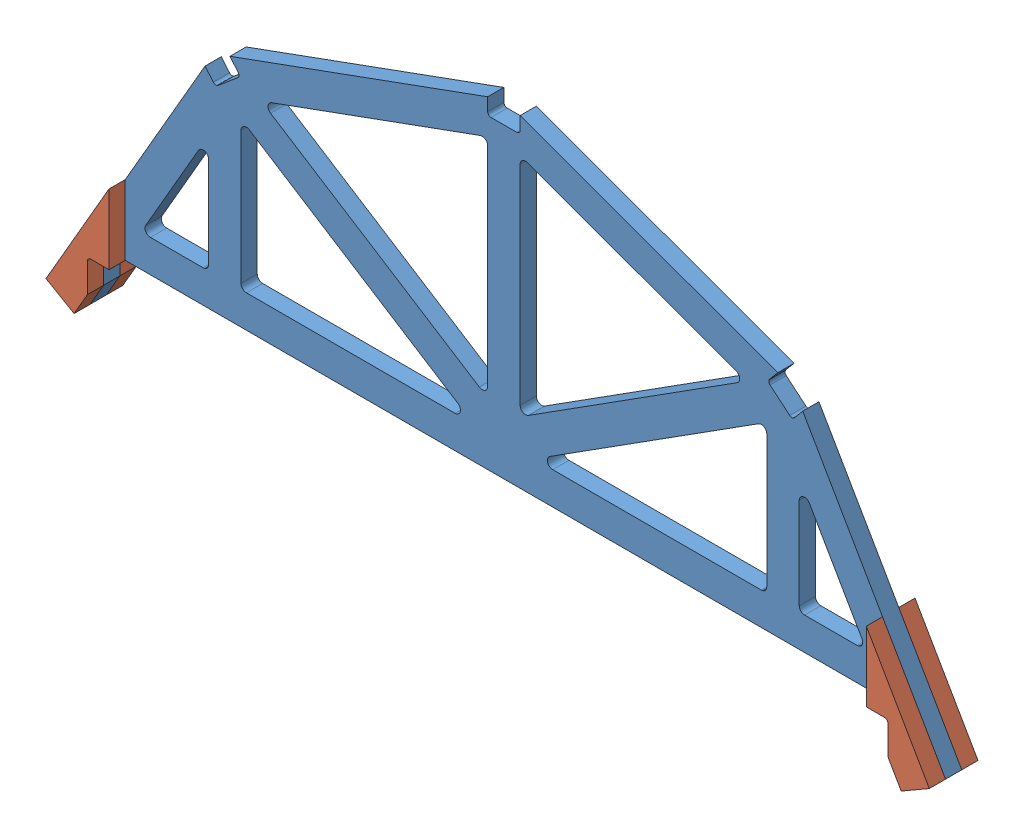
SolidWorks assembly Assem1, configuration Default. Lengths in mm.
Overall size (1036.94 444.07 57.15).
5 component instances, 2 part files, 6 mates.
Components (placement in the parent):
- truss3-1: truss3 [insides] at origin size (1036.94 444.07 19.05)
- truss3-supports-1: truss3-supports [Default] at (0 0 38.1) size (73.97 147.17 19.05)
- truss3-supports-2: truss3-supports [Default] at origin size (73.97 147.17 19.05)
- truss3-supports-5: truss3-supports [Default] x (-1 0 0) z (0 0 -1) size (73.97 147.17 19.05)
- truss3-supports-6: truss3-supports [Default] at (0 0 -38.1) x (-1 0 0) z (0 0 -1) size (73.97 147.17 19.05)
Mates (geometry in assembly coordinates):
- Coincident1: coincident aligned: plane of truss3-1 through (340.6702 439.7326 9.525) normal (0.866025 0.5 0); plane of truss3-supports-1 through (518.4702 131.774 9.525) normal (0.866025 0.5 0)
- Coincident2: coincident aligned: plane of truss3-1 through (485.4746 112.724 9.525) normal (0.5 -0.866025 0); plane of truss3-supports-1 through (485.4746 112.724 9.525) normal (0.5 -0.866025 0)
- Coincident3: coincident aligned: plane of truss3-1 through (340.6702 439.7326 9.525) normal (0.866025 0.5 0); plane of truss3-supports-2 through (518.4702 131.774 -28.575) normal (0.866025 0.5 0)
- Coincident4: coincident aligned: plane of truss3-1 through (485.4746 112.724 9.525) normal (0.5 -0.866025 0); plane of truss3-supports-2 through (485.4746 112.724 -28.575) normal (0.5 -0.866025 0)
- Coincident5: coincident anti-aligned: plane of truss3-1 through (0 0 -9.525) normal (0 0 -1); plane of truss3-supports-2 through (465.9313 173.8312 -9.525) normal (0 0 1)
- Coincident6: coincident anti-aligned: plane of truss3-1 through (0 0 9.525) normal (0 0 1); plane of truss3-supports-1 through (465.9313 173.8312 9.525) normal (0 0 -1)
